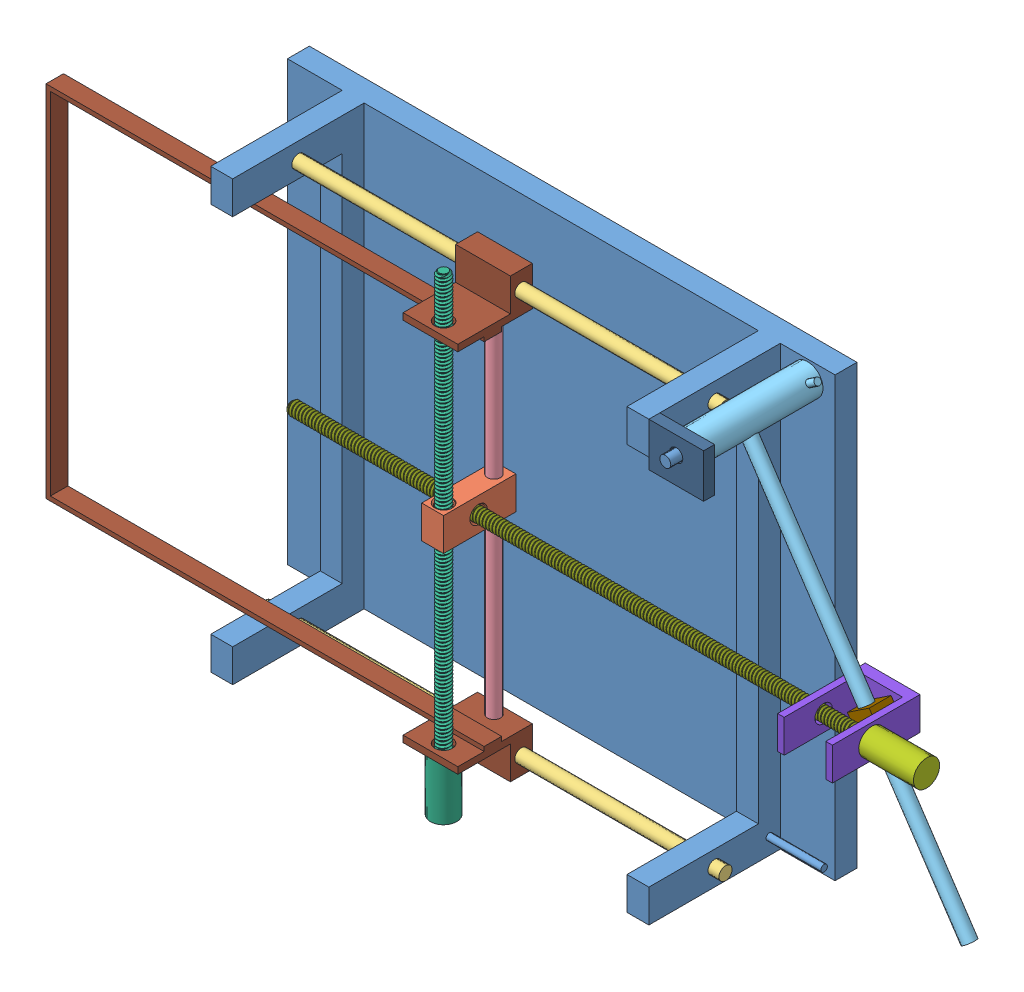
SolidWorks assembly vsa_ut, configuration Défaut. Lengths in mm.
Overall size (414.14 216.44 75).
12 component instances, 11 part files, 27 mates.
Components (placement in the parent):
- base_ut-1: base_ut [Défaut] at (-94.16 45.2956 200) size (250 200 75)
- milieu-1: milieu [Défaut] at (35.1286 -41.6884 268) x (0 -1 0) z (-1 0 0) size (15.74 33 10.38)
- barre1-1: barre1 [Défaut] at (-74.16 -146.7044 240) x (0 -1 0) z (0 0 1) size (6 210 6)
- barre1-2: barre1 [Défaut] at (-74.16 37.2956 240) x (0 0.898626 0.438716) z (0 0.438716 -0.898626) size (6 210 6)
- barre2-1: barre2 [Défaut] at (30.1286 31.2956 240) x (0.563139 0 -0.826362) z (0 -1 0) size (6 6 172)
- cylindre-1: cylindre [Défaut] at (143.34 37.2956 265) x (0.555432 -0.831562 0) z (-0.831562 -0.555432 0) size (194 55 23)
- filetage1-1: filetage1 [Défaut] at (30.1286 -164.7044 263) x (0.888678 0 -0.458532) z (0 1 0) size (12 12 216.44)
- filetage2-1: filetage2 [Défaut] at (239.6188 -49.1884 252) x (0 -0.984109 -0.177566) z (-1 0 0) size (12 12 291.89)
- haut2-1: haut2 [Défaut] at (214.6188 -56.6884 270) x (-1 0 0) z (0 1 0) size (25 40 15)
- haut3-1: haut3 [Défaut] at (211.9748 -51.9577 245) x (-0.831562 -0.555432 0) z (-0.555432 0.831562 0) size (12 10 10)
- haut4-1: haut4 [Défaut] at (155.84 45.2956 270) x (0 -1 0) z (-1 0 0) size (20 5 25)
- fusion_haut-1: fusion_haut [Défaut] at (42.6286 -123.0673 256.4387) x (0 1 0) z (1 0 0) size (200 34 200)
Mates (geometry in assembly coordinates):
- Coaxiale16: concentric anti-aligned: cylinder of base_ut-1 through (-94.16 37.2956 240) axis (1 0 0) radius 3; cylinder of barre1-2 through (135.84 37.2956 240) axis (-1 0 0) radius 3
- Distance1: distance = 5 mm aligned: plane of barre1-2 through (135.84 37.2956 240) normal (1 0 0); plane of base_ut-1 through (130.84 45.2956 270) normal (1 0 0)
- Coaxiale2: concentric anti-aligned: cylinder of base_ut-1 through (-94.16 -146.7044 240) axis (1 0 0) radius 3; cylinder of barre1-1 through (135.84 -146.7044 240) axis (-1 0 0) radius 3
- Distance3: distance = 5 mm aligned: plane of base_ut-1 through (130.84 45.2956 270) normal (1 0 0); plane of barre1-1 through (135.84 -146.7044 240) normal (1 0 0)
- Coaxiale3: concentric anti-aligned: cylinder of base_ut-1 through (143.34 37.2956 275) axis (0 0 -1) radius 2.5; cylinder of cylindre-1 through (143.34 37.2956 210) axis (0 0 1) radius 2.5
- Coïncidente5: coincident anti-aligned: plane of base_ut-1 through (-94.16 45.2956 210) normal (0 0 1); plane of cylindre-1 through (147.228 31.4747 210) normal (0 0 -1)
- Coaxiale4: concentric anti-aligned: cylinder of base_ut-1 through (143.34 37.2956 275) axis (0 0 -1) radius 2.5; cylinder of haut4-1 through (143.34 37.2956 265) axis (0 0 1) radius 3
- Coïncidente8: coincident anti-aligned: plane of base_ut-1 through (130.84 45.2956 270) normal (1 0 0); plane of haut4-1 through (130.84 45.2956 270) normal (-1 0 0)
- Coïncidente9: coincident anti-aligned: plane of cylindre-1 through (143.34 37.2956 265) normal (0 0 1); plane of haut4-1 through (130.84 45.2956 265) normal (0 0 -1)
- Coaxiale5: concentric anti-aligned: cylinder of barre1-1 through (135.84 -146.7044 240) axis (-1 0 0) radius 3; cylinder of fusion_haut-1 through (4.2953 -146.7044 240) axis (1 0 0) radius 3
- Coaxiale6: concentric aligned: cylinder of barre1-2 through (135.84 37.2956 240) axis (-1 0 0) radius 3; cylinder of fusion_haut-1 through (29.2953 37.2956 240) axis (-1 0 0) radius 3
- Coaxiale7: concentric anti-aligned: cylinder of haut2-1 through (207.1188 -49.1884 245) axis (0 0 -1) radius 1; cylinder of haut3-1 through (207.1188 -49.1884 235) axis (0 0 1) radius 1
- Coïncidente10: coincident anti-aligned: plane of haut2-1 through (211.6188 -41.6884 235) normal (0 0 1); plane of haut3-1 through (206.4205 -43.6421 235) normal (0 0 -1)
- Coaxiale8: concentric anti-aligned: cylinder of cylindre-1 through (133.143 52.562 240) axis (-0.555432 0.831562 0) radius 3; cylinder of haut3-1 through (200.1838 -47.8078 240) axis (0.555432 -0.831562 0) radius 3
- Coaxiale9: concentric anti-aligned: circle of milieu-1; cylinder of fusion_haut-1 through (16.7953 45.2956 263) axis (0 -1 0) radius 4
- Coaxiale10: concentric aligned: cylinder of milieu-1 through (16.7953 -41.6884 240) axis (0 -1 0) radius 3; cylinder of fusion_haut-1 through (16.7953 31.2956 240) axis (0 -1 0) radius 3
- Coaxiale11: concentric anti-aligned: cylinder of milieu-1 through (16.7953 -41.6884 240) axis (0 -1 0) radius 3; cylinder of barre2-1 through (16.7953 -140.7044 240) axis (0 1 0) radius 3
- Coïncidente12: coincident anti-aligned: plane of barre2-1 through (16.7953 -140.7044 240) normal (0 -1 0); plane of fusion_haut-1 through (16.7953 -140.7044 240) normal (0 1 0)
- Coïncidente13: coincident anti-aligned: plane of filetage1-1 through (16.7953 -139.7044 263) normal (0 1 0); plane of fusion_haut-1 through (4.2953 -139.7044 269) normal (0 -1 0)
- Coaxiale14: concentric anti-aligned: cone of milieu-1 through (20.7953 -49.1884 252) axis (-1 0 0); cylinder of haut2-1 through (189.6188 -49.1884 252) axis (1 0 0) radius 4
- Hélicoïdale4: screw = 1 aligned: cylinder of milieu-1 through (30.1286 -41.6884 263) axis (0 -1 0) radius 3; cylinder of filetage1-1 through (16.7953 50.2956 263) axis (0 -1 0) radius 3
- Hélicoïdale6: screw = 1 anti-aligned: cone of milieu-1 through (34.1286 -49.1884 252) axis (-1 0 0); cylinder of filetage2-1 through (-50.3812 -49.1884 252) axis (1 0 0) radius 3
- Largeur1: width anti-aligned: plane of fusion_haut-1 through (-168.7047 25.2956 257) normal (0 -1 0); plane of milieu-1 through (-168.7047 -134.7044 257) normal (0 1 0); plane of fusion_haut-1 through (11.7953 -41.6884 268) normal (0 1 0); plane of milieu-1 through (11.7953 -56.6884 268) normal (0 -1 0)
- Largeur2: width anti-aligned: plane of base_ut-1 through (-59.16 45.2956 270) normal (1 0 0); plane of fusion_haut-1 through (120.84 45.2956 270) normal (-1 0 0); plane of base_ut-1 through (4.2953 -154.7044 269) normal (-1 0 0); plane of fusion_haut-1 through (29.2953 27.2956 257) normal (1 0 0)
- Coïncidente16: coincident anti-aligned: plane of filetage2-1 through (214.6188 -49.1884 252) normal (-1 0 0); plane of haut2-1 through (214.6188 -41.6884 270) normal (1 0 0)
- Verrouiller3: lock: unknown of milieu-1; unknown of filetage2-1
- Verrouiller4: lock: unknown of milieu-1; unknown of filetage1-1
